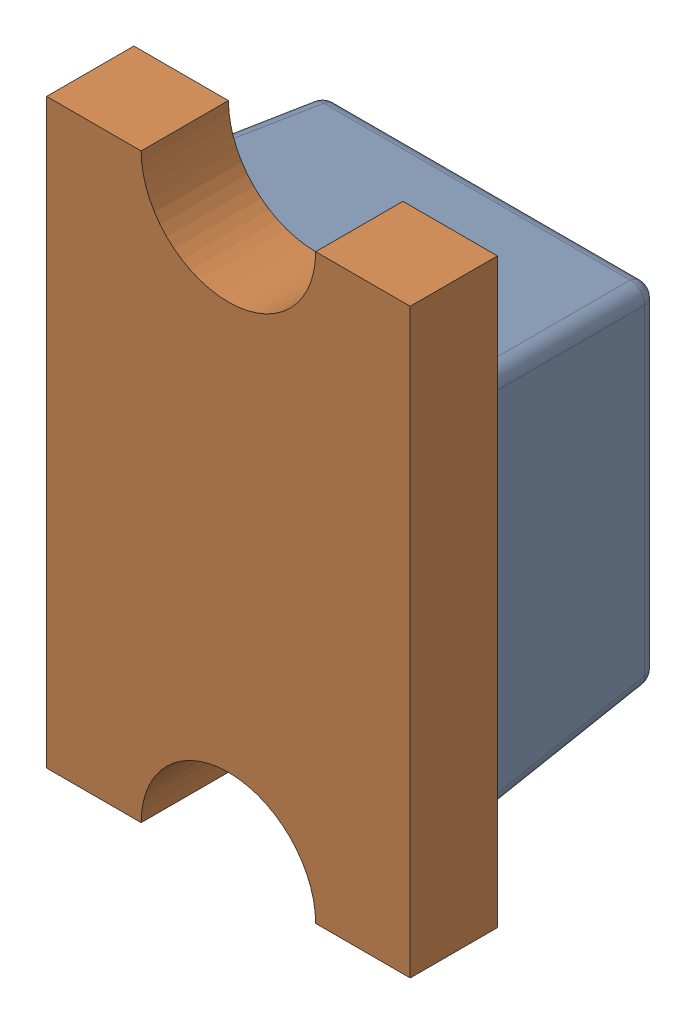
SolidWorks assembly D2_XLR1, configuration Default. Lengths in mm.
Overall size (1.25 2 0.9).
2 component instances, 2 part files, 0 mates.
Components (placement in the parent):
- LED 0805 Lens RED-1: LED 0805 Lens RED [Default] at (165.043 70.1039 -1.2114) x (0 -1 0) z (1 0 0) size (1.3 0.6 1.25)
- LED 0805 Base RED-1: LED 0805 Base RED [Default] at (165.043 70.1039 -1.2114) x (0 -1 0) z (1 0 0) size (2 0.4 1.25)
